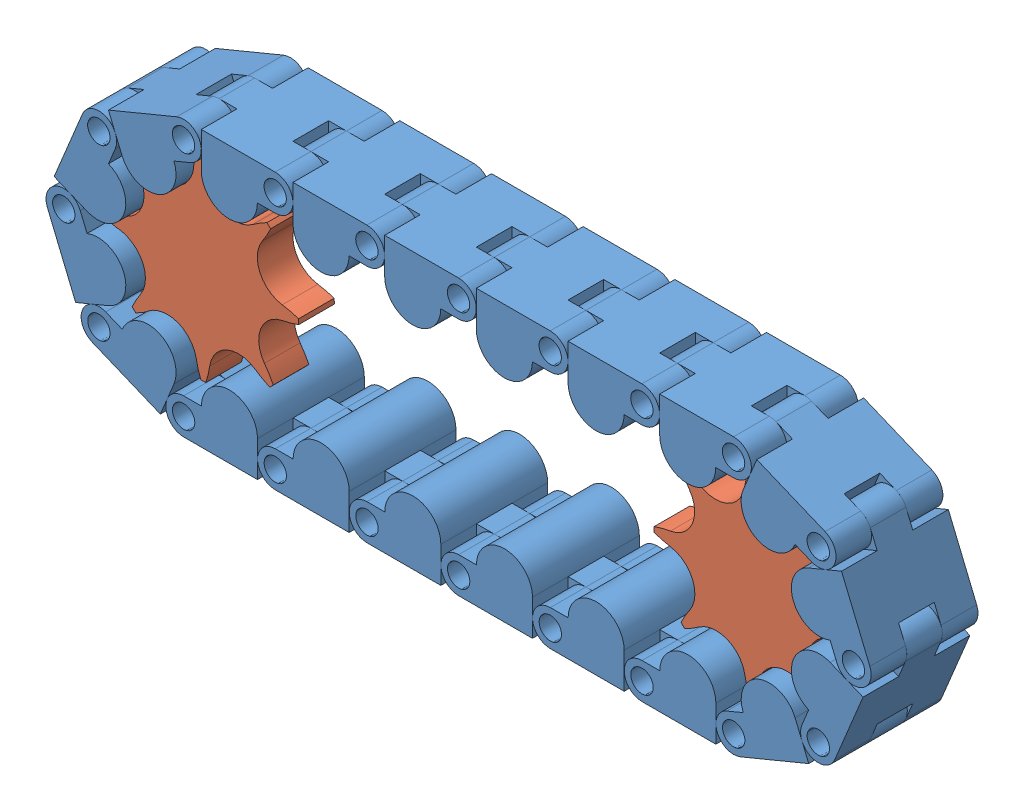
SolidWorks assembly Assem1, configuration Default. Lengths in mm.
Overall size (74.56 25.51 9.53).
22 component instances, 2 part files, 4 mates.
Components (placement in the parent):
- Conveyer Belt Piece-7: Conveyer Belt Piece [Default] at (7.6489 3.1722 0) x (0.383089 -0.923711 0) z (0 0 1) size (11.35 5.67 9.53)
- Conveyer Belt Piece-54: Conveyer Belt Piece [Default] at (3.1655 7.6517 0) x (0.924047 -0.38228 0) z (0 0 1) size (11.35 5.67 9.53)
- Conveyer Belt Piece-55: Conveyer Belt Piece [Default] at (-4.0921 9.0937 0) size (11.35 5.67 9.53)
- Conveyer Belt Piece-56: Conveyer Belt Piece [Default] at (-12.2671 9.0937 0) size (11.35 5.67 9.53)
- Conveyer Belt Piece-57: Conveyer Belt Piece [Default] at (-20.4421 9.0937 0) size (11.35 5.67 9.53)
- Conveyer Belt Piece-58: Conveyer Belt Piece [Default] at (-28.6171 9.0937 0) size (11.35 5.67 9.53)
- Conveyer Belt Piece-59: Conveyer Belt Piece [Default] at (-36.7921 9.0937 0) size (11.35 5.67 9.53)
- Conveyer Belt Piece-60: Conveyer Belt Piece [Default] at (-44.9671 9.0937 0) x (1 0 0) z (0 0 1) size (11.35 5.67 9.53)
- Conveyer Belt Piece-61: Conveyer Belt Piece [Default] at (-52.2222 7.6489 0) x (0.923713 0.383084 0) z (0 0 1) size (11.35 5.67 9.53)
- Conveyer Belt Piece-62: Conveyer Belt Piece [Default] at (-56.7017 3.1656 0) x (0.382285 0.924044 0) z (0 0 1) size (11.35 5.67 9.53)
- Conveyer Belt Piece-63: Conveyer Belt Piece [Default] at (-56.699 -3.1721 0) x (-0.383079 0.923715 0) z (0 0 1) size (11.35 5.67 9.53)
- Conveyer Belt Piece-64: Conveyer Belt Piece [Default] at (-52.2156 -7.6517 0) x (-0.924042 0.38229 0) z (0 0 1) size (11.35 5.67 9.53)
- Conveyer Belt Piece-65: Conveyer Belt Piece [Default] at (-44.958 -9.0937 0) x (-1 0 0) z (0 0 1) size (11.35 5.67 9.53)
- Conveyer Belt Piece-66: Conveyer Belt Piece [Default] at (-36.783 -9.0937 0) x (-1 0 0) z (0 0 1) size (11.35 5.67 9.53)
- Conveyer Belt Piece-67: Conveyer Belt Piece [Default] at (-28.608 -9.0937 0) x (-1 0 0) z (0 0 1) size (11.35 5.67 9.53)
- Conveyer Belt Piece-69: Conveyer Belt Piece [Default] at (-20.433 -9.0937 0) x (-1 0 0) z (0 0 1) size (11.35 5.67 9.53)
- Conveyer Belt Piece-70: Conveyer Belt Piece [Default] at (-12.258 -9.0937 0) x (-1 0 0) z (0 0 1) size (11.35 5.67 9.53)
- Conveyer Belt Piece-71: Conveyer Belt Piece [Default] at (-4.083 -9.0937 0) x (-1 0 0) z (0 0 1) size (11.35 5.67 9.53)
- Conveyer Belt Piece-72: Conveyer Belt Piece [Default] at (3.1721 -7.649 0) x (-0.923718 -0.383074 0) z (0 0 1) size (11.35 5.67 9.53)
- Conveyer Belt Piece-73: Conveyer Belt Piece [Default] at (7.6516 -3.1656 0) x (-0.382295 -0.92404 0) z (0 0 1) size (11.35 5.67 9.53)
- Conveyer Belt Gear2-1: Conveyer Belt Gear2 [Default] x (0.003166 -0.999995 0) z (0 0 1) size (17.36 17.36 3.17)
- Conveyer Belt Gear2-2: Conveyer Belt Gear2 [Default] at (-49.05 0 0) x (0.721006 -0.692929 0) z (0 0 1) size (17.36 17.36 3.17)
Mates (geometry in assembly coordinates):
- Coincident18: coincident: point of Conveyer Belt Gear2-1
- Coincident19: coincident aligned: plane of Conveyer Belt Piece-7 through (7.6489 3.1722 0) normal (0 0 1); plane of Conveyer Belt Gear2-1 through (0 0 0) normal (0 0 1)
- Coincident20: coincident: unknown of Conveyer Belt Gear2-2
- Coincident21: coincident aligned: plane of Conveyer Belt Gear2-1 through (0 0 3.175) normal (0 0 1); plane of Conveyer Belt Gear2-2 through (-49.05 0 3.175) normal (0 0 1)
